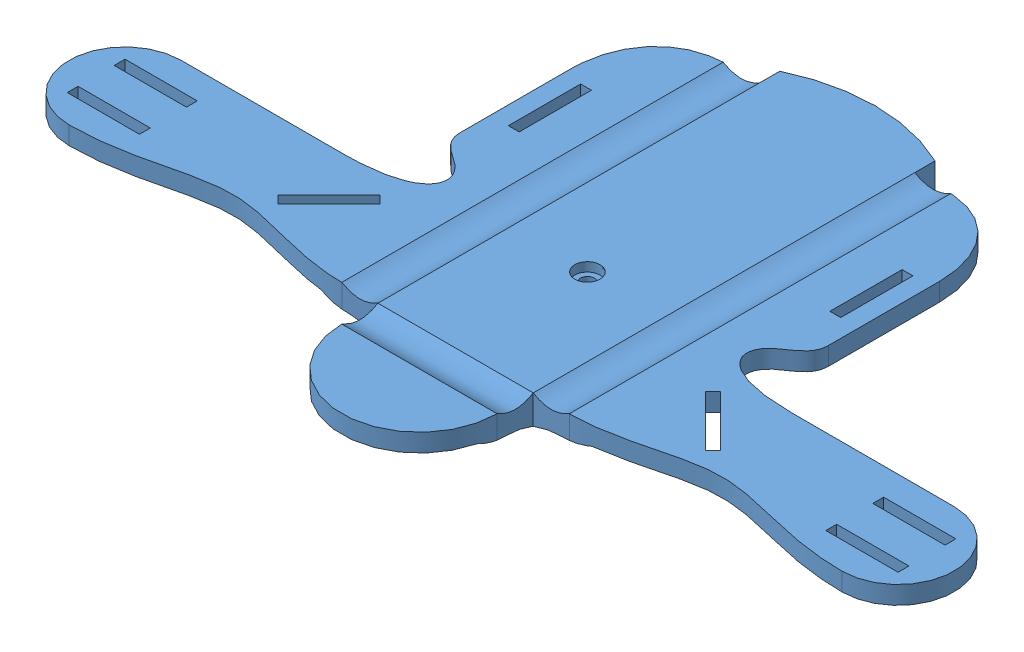
SolidWorks assembly ClubFootSandalAssembled, configuration Default. Lengths in mm.
Overall size (330 15.5 245).
2 component instances, 2 part files, 3 mates.
Components (placement in the parent):
- ClubFootSandalBase-1: ClubFootSandalBase [Default] at (-81.6371 -7.4146 23.8317) size (330 14.64 245)
- ClubFootGearF-1: ClubFootGearF [Default] at (-39.1371 -9.9146 -12.6683) x (0.992115 0 0.125333) z (0.125333 0 -0.992115) size (60 5 60)
Mates (geometry in assembly coordinates):
- Concentric1: concentric aligned: cylinder of ClubFootSandalBase-1 through (-39.1371 0.5864 -12.6683) axis (0 -1 0) radius 2; cylinder of ClubFootGearF-1 through (-39.1371 -9.9136 -12.6683) axis (0 -1 0) radius 2
- Coincident1: coincident anti-aligned: plane of ClubFootSandalBase-1 through (-39.1371 -9.9146 -12.6683) normal (0 -1 0); plane of ClubFootGearF-1 through (-39.1371 -9.9146 -12.6683) normal (0 1 0)
- Parallel1: parallel anti-aligned: plane of ClubFootSandalBase-1 through (-60.6371 0.5854 -87.3991) normal (-1 0 0); line of ClubFootGearF-1 through (-40.7072 -14.9146 -37.6272) axis (0 0 -1)
